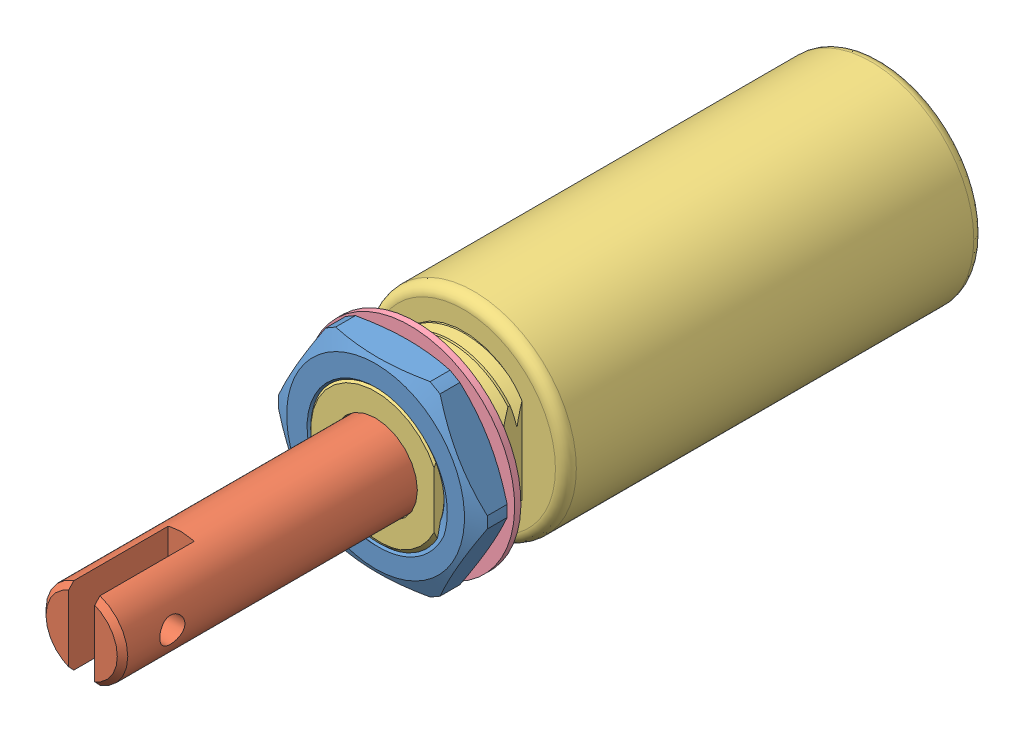
SolidWorks assembly DSTL-0840, configuration Deactivated (Extended). Lengths in mm.
Overall size (28.14 28.14 76.5).
4 component instances, 4 part files, 8 mates.
Components (placement in the parent):
- DSTL-0840 nut_╣w│]-1: DSTL-0840 nut_╣w│] [Default] at (0 0 45.1) x (0.866025 0.5 0) z (0 0 1) size (17.84 20 4.05)
- DSTL-0840 plunger_╣w│]-1: DSTL-0840 plunger_╣w│] [Default] at (0 0 76.5) x (0 1 0) z (1 0 0) size (7.82 55.6 7.82)
- DSTL-0840 body_╣w│]-1: DSTL-0840 body_╣w│] [Default] at origin size (19.6 19.6 48.81)
- DSTL-0840 washer_╣w│]-1: DSTL-0840 washer_╣w│] [Default] at (0 0 45.1) x (-0.775263 -0.631639 0) z (0 0 -1) size (20 20 0.93)
Mates (geometry in assembly coordinates):
- Concentric1: concentric anti-aligned: cylinder of DSTL-0840 body_╣w│]-1 through (0 0 40) axis (0 0 -1) radius 9.8; cylinder of DSTL-0840 washer_╣w│]-1 through (0 0 44.5) axis (0 0 1) radius 10
- Concentric2: concentric anti-aligned: circle of DSTL-0840 nut_╣w│]-1; cylinder of DSTL-0840 body_╣w│]-1 through (0 0 40) axis (0 0 -1) radius 9.8
- Coincident1: coincident anti-aligned: plane of DSTL-0840 nut_╣w│]-1 through (0 0 45.1) normal (0 0 -1); plane of DSTL-0840 washer_╣w│]-1 through (0 0 45.1) normal (0 0 1)
- Concentric3: concentric aligned: cylinder of DSTL-0840 plunger_╣w│]-1 through (0 0 76.5) axis (0 0 -1) radius 3.91; cylinder of DSTL-0840 body_╣w│]-1 through (0 0 40) axis (0 0 -1) radius 9.8
- Distance1: distance = 36.5 mm aligned: plane of DSTL-0840 plunger_╣w│]-1 through (0 0 76.5) normal (0 0 1); plane of DSTL-0840 body_╣w│]-1 through (0 0 40) normal (0 0 1)
- Parallel1: parallel aligned: plane of DSTL-0840 plunger_╣w│]-1 through (-1.25 -3.7048 67) normal (1 0 0); plane of DSTL-0840 body_╣w│]-1 through (5.6 6.7882 26.0515) normal (1 0 0)
- Perpendicular1: perpendicular: plane of DSTL-0840 nut_╣w│]-1 through (11.4007 8.9201 38.4) normal (0 1 0); plane of DSTL-0840 plunger_╣w│]-1 through (-1.25 -3.7048 67) normal (1 0 0)
- Coincident2: coincident aligned: plane of DSTL-0840 nut_╣w│]-1 through (0 0 48.4) normal (0 0 1); plane of DSTL-0840 body_╣w│]-1 through (0 0 48.4) normal (0 0 1)
